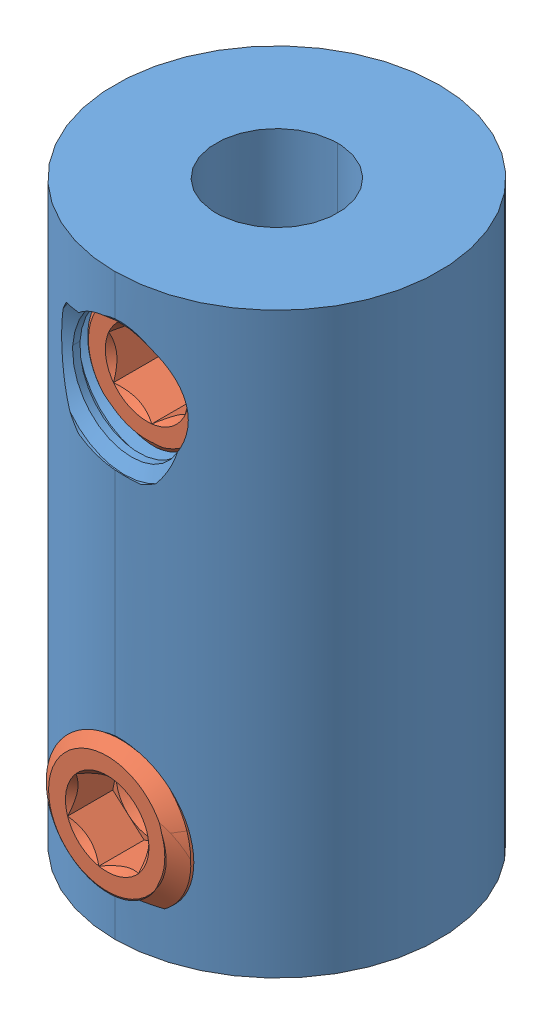
SolidWorks assembly 4mm to 6mm, configuration Default. Lengths in mm.
Overall size (10.67 19.05 10.93).
4 component instances, 2 part files, 0 mates.
Components (placement in the parent):
- 625220 assembly.STEP-1: 625220 assembly.STEP [Default] at origin size (10.67 19.05 10.93)
  - 625220.STEP-1: 625220.STEP [Default] at (-25.1618 4.7538 3.53) size (10.67 19.05 10.67)
  - 632134_91375A436.STEP-1: 632134_91375A436.STEP [Default] at (-25.1618 8.1828 7.9297) x (-0.317738 0.948179 0) z (0 0 1) size (4.83 4.83 3.18)
  - 632134_91375A436.STEP-2: 632134_91375A436.STEP [Default] at (-25.1618 20.3748 6.6171) x (0.993493 0.113893 0) z (0 0 1) size (4.83 4.83 3.18)
